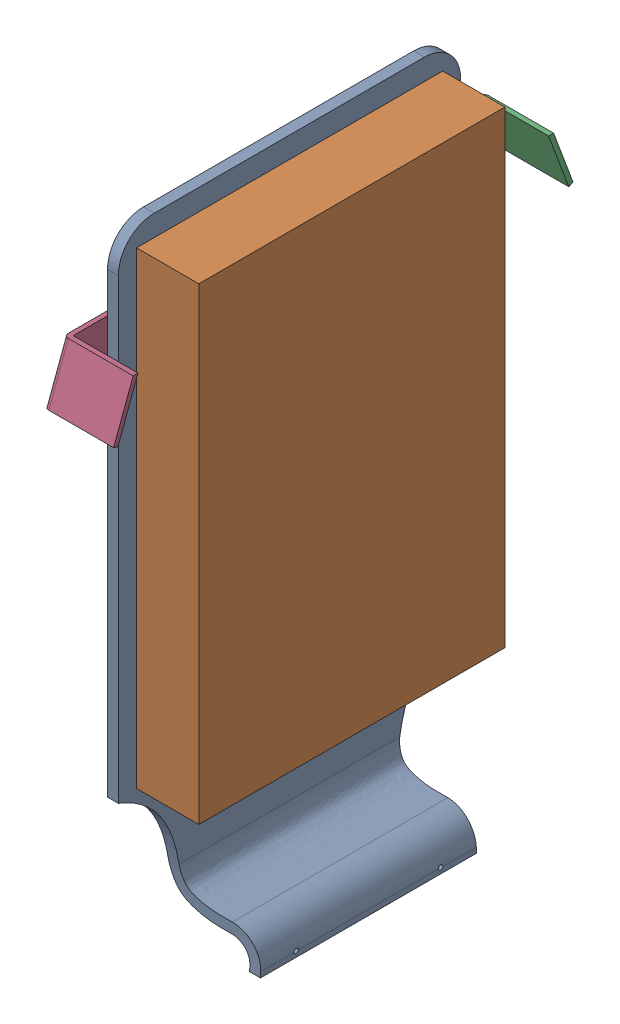
SolidWorks assembly MS-70001-XA-Head Restraint Assembly1, configuration Default. Lengths in mm.
Overall size (66.68 448.8 324.07).
4 component instances, 4 part files, 1 mates.
Components (placement in the parent):
- MS-70001-AG-Head_Restraint1-1: MS-70001-AG-Head_Restraint1 [Default] at (207.0378 -6.087 347.9488) size (66.44 448.8 241.3)
- MS-70001-AB-Head Restraint Padding1-1: MS-70001-AB-Head Restraint Padding1 [Default] at (158.9013 216.3377 354.6269) size (43.94 330.2 215.9)
- MS-70001-AC-Right Head Restraint Tab1-2: MS-70001-AC-Right Head Restraint Tab1 [Default] at (147.9793 388.883 235.0151) x (0 0 1) z (-1 0 0) size (49.06 38.1 49.02)
- MS-70001-AC-Left Head Restraint Tab1-3: MS-70001-AC-Left Head Restraint Tab1 [Default] at (151.2813 388.883 461.0827) x (0 0 -1) z (1 0 0) size (48.94 38.1 48.89)
Mates (geometry in assembly coordinates):
- Coincident5: coincident anti-aligned: plane of MS-70001-AG-Head_Restraint-1 through (158.9013 36.3112 468.5988) normal (1 0 0); plane of MS-70001-AB-Head Restraint Padding-1 through (158.9013 216.3377 354.6269) normal (-1 0 0)
